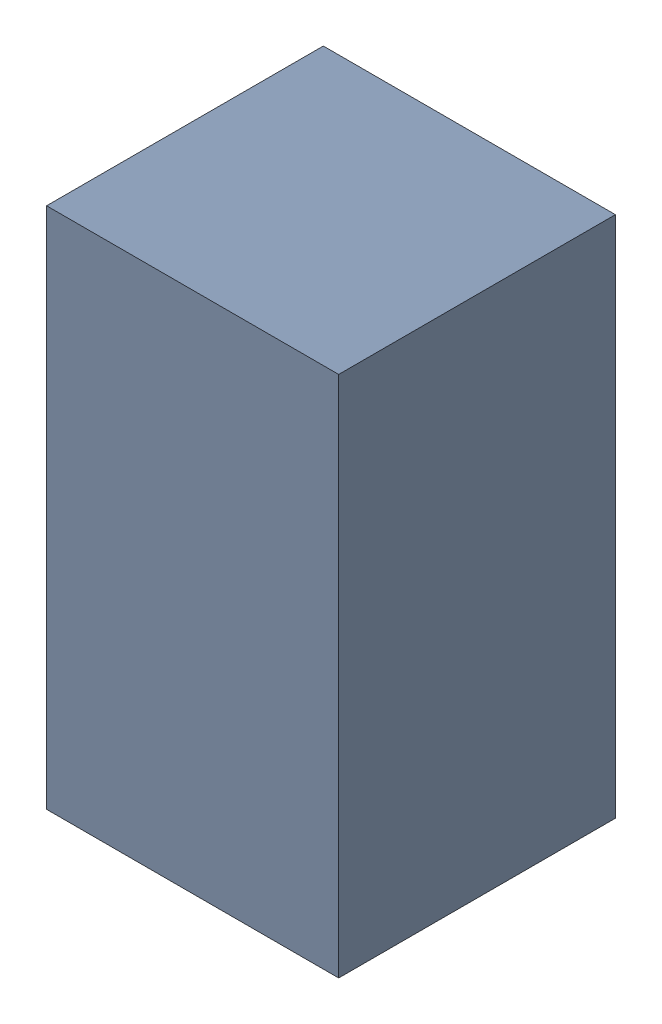
SolidWorks assembly R1_1, configuration Default. Lengths in mm.
Overall size (0.95 1.7 0.9).
2 component instances, 1 part files, 0 mates.
Components (placement in the parent):
- 5808185088-1: 5808185088 [Default] at (10.045 9.767 0) size (0.95 1.7 0.9)
  - Extruded_1_2-1: Extruded_1_2 [Default] at origin size (0.95 1.7 0.9)
